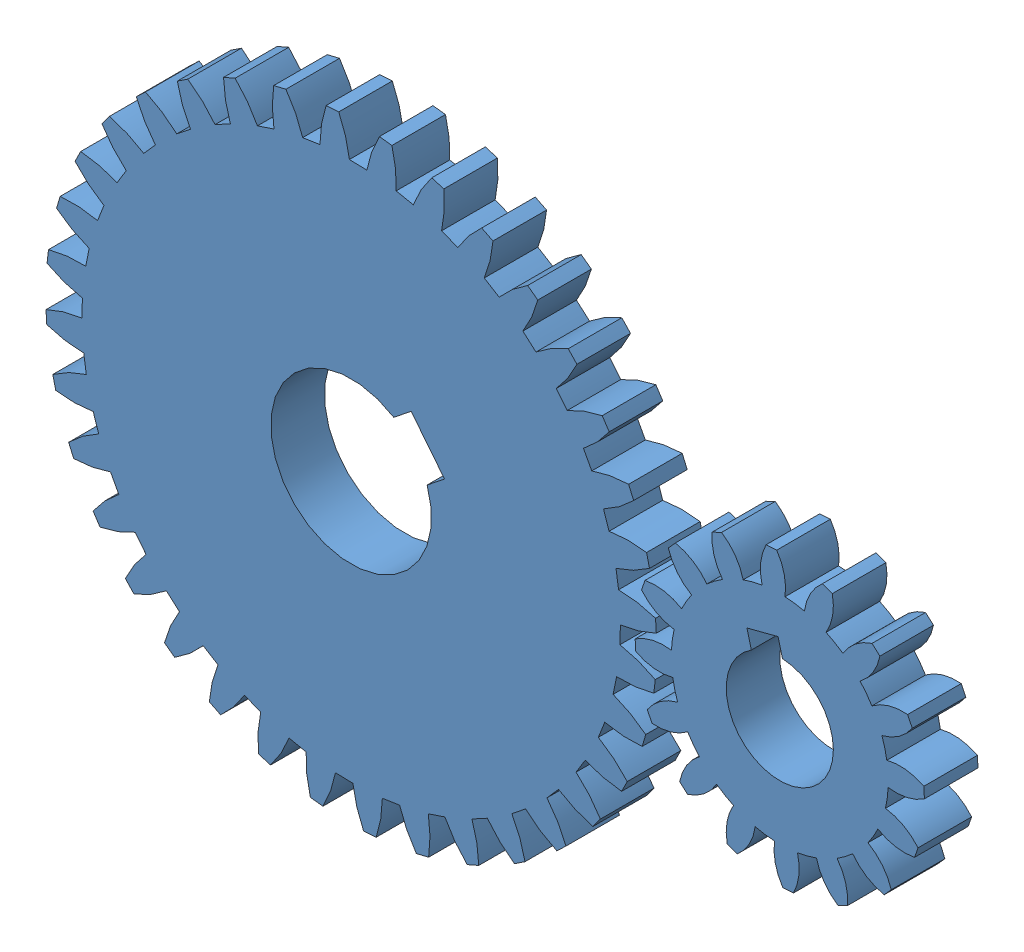
SolidWorks assembly First_Test, configuration Default. Lengths in mm.
Overall size (192.42 159.83 10).
2 component instances, 1 part files, 4 mates.
Components (placement in the parent):
- spur gear_am-3: spur gear_am [Metric - Spur gear 3M 36T 14.5PA 10FW ---S36N75H50L30R1] x (0 0 -1) z (0.622708 -0.782455 0) size (10 113.75 113.75)
- spur gear_am-4: spur gear_am [Metric - Spur gear 3M 16T 14.5PA 10FW ---S16N75H50L20S1] at (80 0 0) x (0 0 -1) z (0.967898 0.251345 0) size (10 53.31 53.31)
Mates (geometry in assembly coordinates):
- Coincident1: coincident aligned: plane of spur gear_am-3 through (0 0 0) normal (0 0 1)
- Coincident2: coincident aligned: plane of spur gear_am-4 through (80 0 0) normal (0 0 1)
- Concentric1: concentric aligned: circle of spur gear_am-3
- Concentric3: concentric aligned: circle of spur gear_am-4
